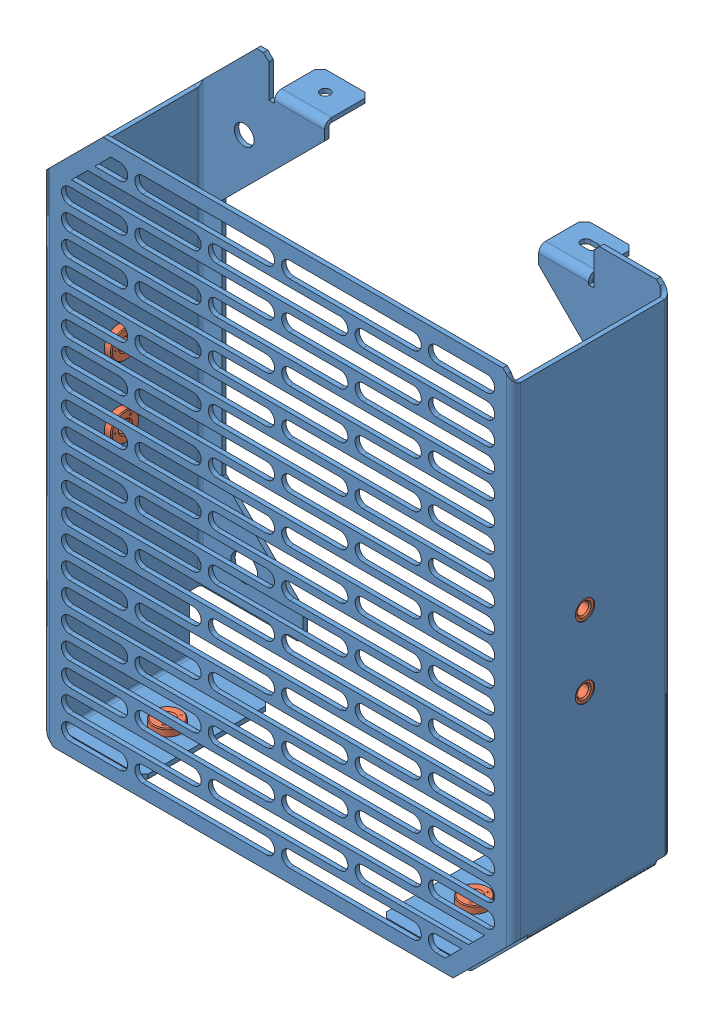
SolidWorks assembly TE-1719_742928-04_SC1-Rear-Grill, configuration Default. Lengths in mm.
Overall size (132 155 55.8).
7 component instances, 2 part files, 8 mates.
Components (placement in the parent):
- TE-1719_742926-04_742928-04_MASTER-MODEL_SC1-FRONT-REAR-1: TE-1719_742926-04_742928-04_MASTER-MODEL_SC1-FRONT-REAR [Rear_PEM-Nuts] at origin size (132 155 55.8)
- PEM-Nut_S-M4-1ZI-1: PEM-Nut_S-M4-1ZI [Default] at (65.7508 89 -20) x (-1 0 0) z (0 0 -1) size (2.97 7.87 7.87)
- PEM-Nut_S-M4-1ZI-2: PEM-Nut_S-M4-1ZI [Default] at (65.7508 69 -20) x (-1 0 0) z (0 0 -1) size (2.97 7.87 7.87)
- PEM-Nut_S-M4-1ZI-3: PEM-Nut_S-M4-1ZI [Default] at (35 1.4492 -20) x (0 1 0) z (-1 0 0) size (2.97 7.87 7.87)
- PEM-Nut_S-M4-1ZI-9: PEM-Nut_S-M4-1ZI [Default] at (-65.7508 89 -20) size (2.97 7.87 7.87)
- PEM-Nut_S-M4-1ZI-10: PEM-Nut_S-M4-1ZI [Default] at (-65.7508 69 -20) size (2.97 7.87 7.87)
- PEM-Nut_S-M4-1ZI-8: PEM-Nut_S-M4-1ZI [Default] at (-51 1.4492 -20) x (0 1 0) z (-1 0 0) size (2.97 7.87 7.87)
Mates (geometry in assembly coordinates):
- Concentric1: concentric aligned: cylinder of TE-1719_742926-04_742928-04_MASTER-MODEL_SC1-FRONT-REAR-1 through (66 89 -20) axis (-1 0 0) radius 2.7178; cylinder of PEM-Nut_S-M4-1ZI-1 through (63.8988 89 -20) axis (-1 0 0) radius 3.935
- Coincident1: coincident aligned: plane of TE-1719_742926-04_742928-04_MASTER-MODEL_SC1-FRONT-REAR-1 through (64.7808 0 0) normal (-1 0 0); circle of PEM-Nut_S-M4-1ZI-1
- Concentric2: concentric aligned: cylinder of TE-1719_742926-04_742928-04_MASTER-MODEL_SC1-FRONT-REAR-1 through (66 69 -20) axis (-1 0 0) radius 2.7178; cylinder of PEM-Nut_S-M4-1ZI-2 through (63.8988 69 -20) axis (-1 0 0) radius 3.935
- Coincident2: coincident aligned: plane of TE-1719_742926-04_742928-04_MASTER-MODEL_SC1-FRONT-REAR-1 through (64.7808 0 0) normal (-1 0 0); circle of PEM-Nut_S-M4-1ZI-2
- Concentric3: concentric anti-aligned: cylinder of TE-1719_742926-04_742928-04_MASTER-MODEL_SC1-FRONT-REAR-1 through (35 156.2 -20) axis (0 -1 0) radius 2.7178; cylinder of PEM-Nut_S-M4-1ZI-3 through (35 3.3012 -20) axis (0 1 0) radius 3.935
- Coincident3: coincident aligned: plane of TE-1719_742926-04_742928-04_MASTER-MODEL_SC1-FRONT-REAR-1 through (0.3571 2.4192 0) normal (0 1 0); circle of PEM-Nut_S-M4-1ZI-3
- Concentric4: concentric anti-aligned: cylinder of TE-1719_742926-04_742928-04_MASTER-MODEL_SC1-FRONT-REAR-1 through (-51 156.2 -20) axis (0 -1 0) radius 2.7178; cylinder of PEM-Nut_S-M4-1ZI-8 through (-51 3.3012 -20) axis (0 1 0) radius 3.935
- Coincident4: coincident aligned: circle of PEM-Nut_S-M4-1ZI-8; plane of TE-1719_742926-04_742928-04_MASTER-MODEL_SC1-FRONT-REAR-1 through (0 2.4192 0) normal (0 1 0)
